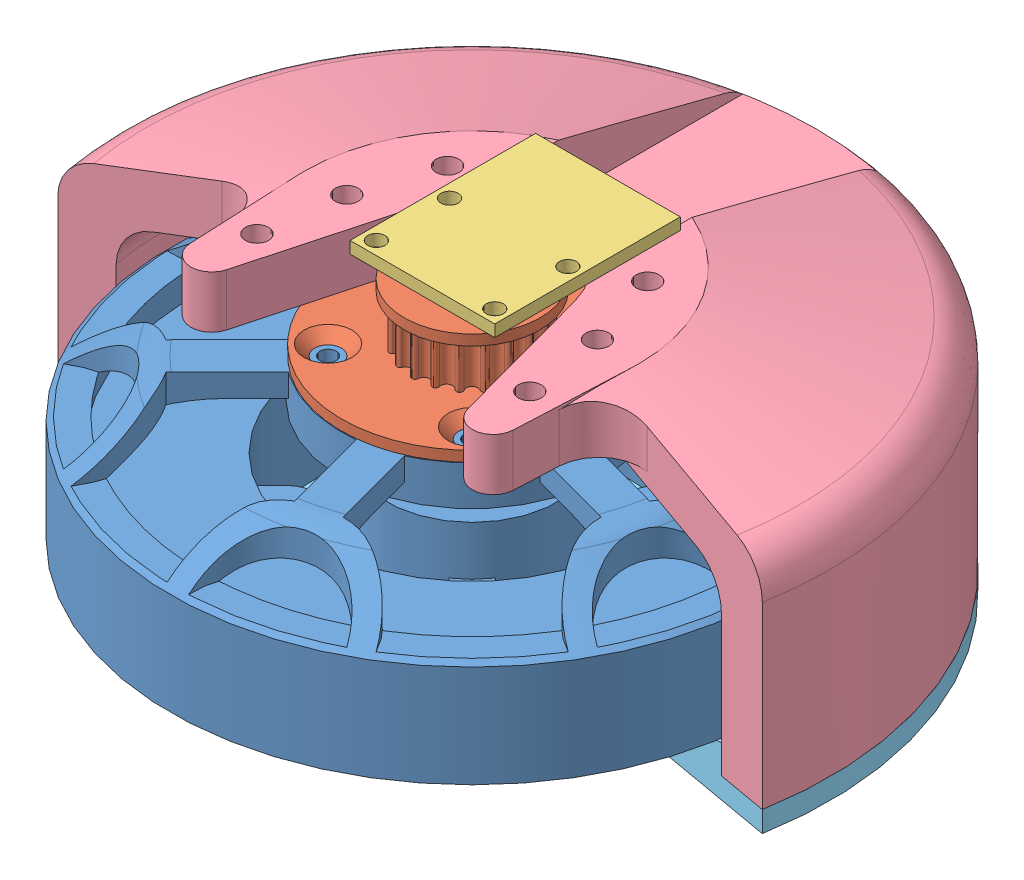
SolidWorks assembly MotorPulleyHall, configuration Default. Lengths in mm.
Overall size (221.44 70.21 221.44).
5 component instances, 5 part files, 10 mates.
Components (placement in the parent):
- 9225 160kv-1: 9225 160kv [Default] at (0 -3.93 0) x (0.707107 0 0.707107) z (-0.707107 0 0.707107) size (156.58 62.73 156.58)
- 20 tooth htd 3mm pulley-1: 20 tooth htd 3mm pulley [Default] at (0 33.3375 0) x (0.707107 0 0.707107) z (-0.707107 0 0.707107) size (39.69 10.17 39.69)
- AS5047D Dev Board-1: AS5047D Dev Board [Default] at (0 41.7308 0) x (-1 0 0) z (0 0 1) size (22 6.88 28.22)
- Copy of Part1^MotorPulleyHall-1: Copy of Part1^MotorPulleyHall [Default] at (0 65.7833 0) x (-1 0 0) z (0 0 1) size (108.81 39.93 75.78) (virtual)
- MotorMountPlate-1: MotorMountPlate [Default] at origin size (114.06 7.53 81.9)
Mates (geometry in assembly coordinates):
- Coincident2: coincident aligned: line of 9225 160kv-1 through (41.998 0 36.159) axis (0 0 -1)
- Coincident3: coincident anti-aligned: plane of 9225 160kv-1 through (6.8236 0 6.8236) normal (0 -1 0)
- Angle1: planar angle = 0.785398 rad aligned: plane of 9225 160kv-1 through (0 -3.93 0) normal (-0.707107 0 0.707107)
- Coincident12: coincident: point of AS5047D Dev Board-1
- Concentric4: concentric aligned: cylinder of 9225 160kv-1 through (0 34.25 0) axis (0 1 0) radius 1.5; cylinder of 15 tooth htd 3mm pulley-1 through (0 35.25 0) axis (0 1 0) radius 3.175
- Concentric5: concentric anti-aligned: cylinder of 9225 160kv-1 through (-10.9602 28.25 10.9602) axis (0 1 0) radius 1.25; cone of 15 tooth htd 3mm pulley-1 through (-10.9602 26.2053 10.9602) axis (0 -1 0)
- Coincident14: coincident anti-aligned: plane of 9225 160kv-1 through (22.981 28.25 22.981) normal (0 1 0); plane of 15 tooth htd 3mm pulley-1 through (0 28.25 0) normal (0 -1 0)
- Parallel1: parallel anti-aligned: plane of AS5047D Dev Board-1 through (0 39.9308 0) normal (0 -1 0)
- Coincident16: coincident anti-aligned: plane of AS5047D Dev Board-1 through (0 41.7308 0) normal (-1 0 0)
- Coincident20: coordinate: point of assembly; point of MotorMountPlate-1; point of assembly
